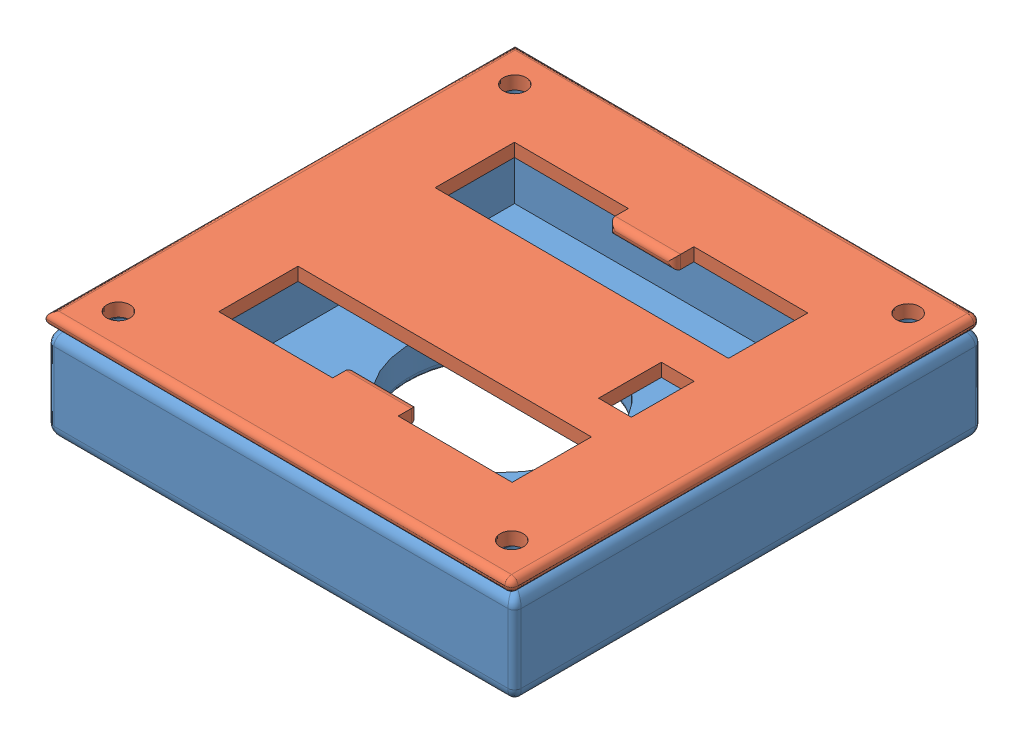
SolidWorks assembly assembly, configuration Default. Lengths in mm.
Overall size (71.28 16.5 71.28).
2 component instances, 2 part files, 1 mates.
Components (placement in the parent):
- Part1-2: Part1 [Default] at (76.7221 30.8149 79.1881) size (71 14.5 71)
- Part2-4: Part2 [Default] at (76.4936 45.3149 79.4357) x (0.999992 0 0.003898) z (-0.003898 0 0.999992) size (71 2 71)
Mates (geometry in assembly coordinates):
- Coincident3: coincident anti-aligned: plane of Part1-2 through (76.7221 45.3149 79.1881) normal (0 1 0); plane of Part2-4 through (76.4936 45.3149 79.4357) normal (0 -1 0)
